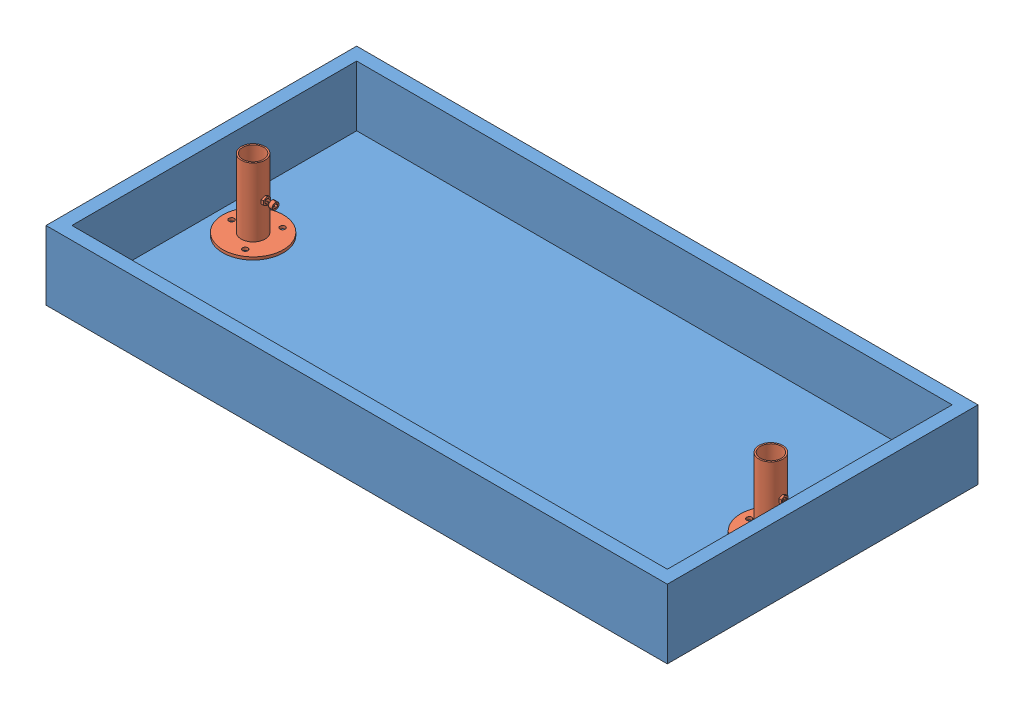
SolidWorks assembly 1100-BaseAsm, configuration Default. Lengths in mm.
Overall size (914.4 117.35 457.2).
3 component instances, 2 part files, 4 mates.
Components (placement in the parent):
- 6001-Base-1: 6001-Base [Default] at origin size (914.4 101.6 457.2)
- 6005-ClampFitting-4: 6005-ClampFitting [2534T82] at (838.2 0 -228.6) x (1 0 0) z (0 1 0) size (88.9 88.9 104.65)
- 6005-ClampFitting-5: 6005-ClampFitting [2534T82] at (76.2 0 -228.6) x (1 0 0) z (0 1 0) size (88.9 88.9 104.65)
Mates (geometry in assembly coordinates):
- Coincident9: coincident aligned: plane of 6001-Base-1 through (0 0 0) normal (0 1 0); circle of 6005-ClampFitting-4
- Concentric2: concentric anti-aligned: circle of 6001-Base-1; circle of 6005-ClampFitting-4
- Coincident10: coincident anti-aligned: plane of 6001-Base-1 through (0 0 0) normal (0 1 0); plane of 6005-ClampFitting-5 through (76.2 0 -228.6) normal (0 -1 0)
- Concentric4: concentric aligned: circle of 6001-Base-1; circle of 6005-ClampFitting-5
